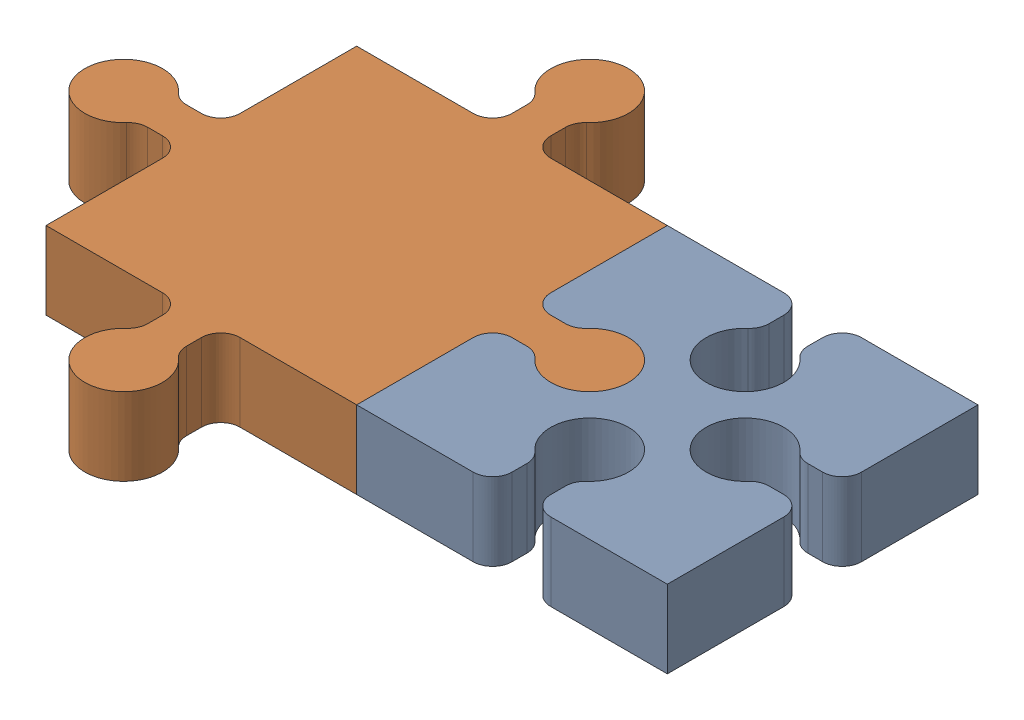
SolidWorks assembly Assem1, configuration Default. Lengths in mm.
Overall size (19 2 14).
2 component instances, 2 part files, 1 mates.
Components (placement in the parent):
- piece2-1: piece2 [Default] at origin size (8 2 8)
- piece1-2: piece1 [Default] at (-8 0 0) size (14 2 14)
Mates (geometry in assembly coordinates):
- Coincident1: coincident aligned: circle of piece2-1; circle of piece1-2
